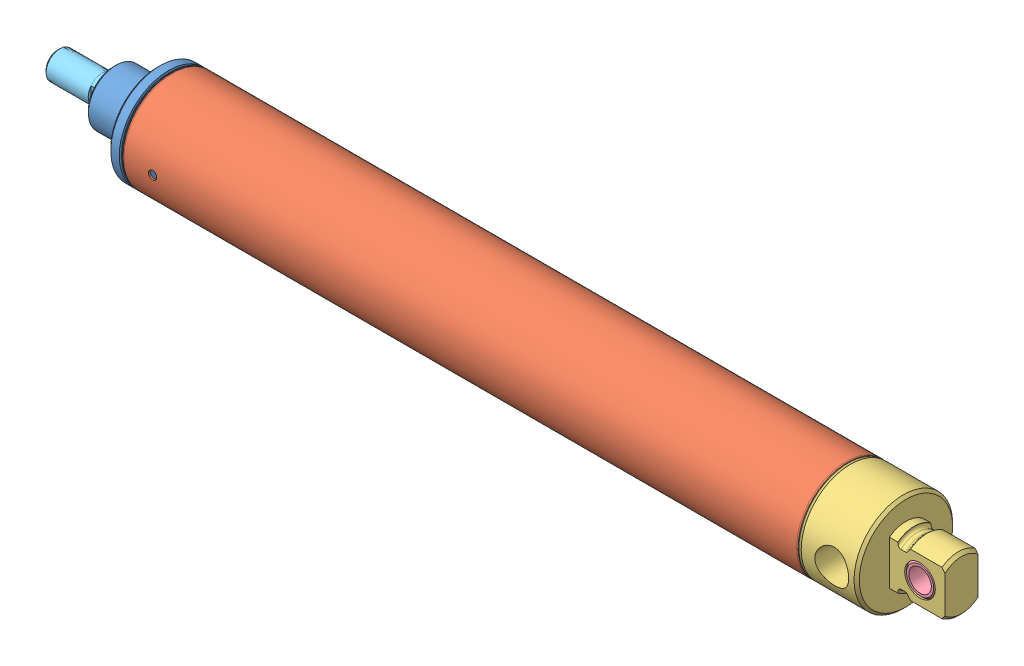
SolidWorks assembly 093_5-HPY, configuration Default. Lengths in mm.
Overall size (258.6 28.27 28.27).
6 component instances, 6 part files, 14 mates.
Components (placement in the parent):
- 093_5-HPCY0000_0_dummy-1: 093_5-HPCY0000_0_dummy [Default] at origin
- 09000-0_rod_guide-1: 09000-0_rod_guide [Default] at origin size (25.4 28.27 28.27)
- 09-7_6212C-1: 09-7_6212C [Default] at (16.637 0 0) size (194.93 28.27 28.27)
- 09P0Y000_rear_head-1: 09P0Y000_rear_head [Default] at (204.6224 0 0) size (38.1 28.22 28.22)
- D-3543-1: D-3543 [Default] at (235.585 0 0) x (1 0 0) z (0 0 -1) size (8.78 8.78 9.4)
- C-093_5-HPY0_rod-1: C-093_5-HPY0_rod [Default] at origin size (220.5 27.11 27.11)
Mates (geometry in assembly coordinates):
- Distance2: distance = 0 mm aligned: plane of 09000-0_rod_guide-1 through (0 0 0) normal (1 0 0); plane of 093_5-HPCY0000_0_dummy-1 through (0 0 0) normal (1 0 0)
- Coincident1: coincident aligned: line of 093_5-HPCY0000_0_dummy-1 through (80.9 0 0) axis (-1 0 0); line of 09000-0_rod_guide-1 through (80.9 0 0) axis (-1 0 0)
- Angle3: planar angle = 0 rad aligned: plane of 09000-0_rod_guide-1 through (0 0 0) normal (0 0 -1); plane of 093_5-HPCY0000_0_dummy-1 through (0 0 0) normal (0 0 -1)
- Distance4: distance = 0 mm aligned: plane of 09-7_6212C-1 through (16.637 0 0) normal (1 0 0); plane of 09000-0_rod_guide-1 through (16.637 0 0) normal (1 0 0)
- Coincident2: coincident aligned: line of 09000-0_rod_guide-1 through (80.9 0 0) axis (-1 0 0); line of 09-7_6212C-1 through (97.537 0 0) axis (-1 0 0)
- Angle6: planar angle = 0 rad aligned: plane of 09-7_6212C-1 through (16.637 0 0) normal (0 0 -1); plane of 09000-0_rod_guide-1 through (0 0 0) normal (0 0 -1)
- Distance6: distance = 0 mm aligned: plane of 09P0Y000_rear_head-1 through (210.2104 0 0) normal (1 0 0); plane of 09-7_6212C-1 through (210.2104 0 0) normal (1 0 0)
- Coincident3: coincident aligned: line of 09-7_6212C-1 through (97.537 0 0) axis (-1 0 0); line of 09P0Y000_rear_head-1 through (285.5224 0 0) axis (-1 0 0)
- Angle9: planar angle = 0 rad aligned: plane of 09P0Y000_rear_head-1 through (204.6224 0 0) normal (0 0 -1); plane of 09-7_6212C-1 through (16.637 0 0) normal (0 0 -1)
- Distance7: distance = 0 mm anti-aligned: plane of D-3543-1 through (235.585 0 0) normal (0 0 -1); plane of 09P0Y000_rear_head-1 through (204.6224 0 0) normal (0 0 1)
- Coincident4: coincident anti-aligned: line of 09P0Y000_rear_head-1 through (235.585 0 80.9) axis (0 0 -1); line of D-3543-1 through (235.585 0 -80.9) axis (0 0 1)
- Angle12: planar angle = 0 rad aligned: plane of D-3543-1; plane of 09P0Y000_rear_head-1 through (235.585 0 0) normal (1 0 0)
- LimitDistance2: limit distance = 0 mm aligned: plane of C-093_5-HPY0_rod-1 through (0 0 0) normal (1 0 0); plane of 09000-0_rod_guide-1 through (0 0 0) normal (1 0 0)
- Coincident5: coincident aligned: line of 09000-0_rod_guide-1 through (80.9 0 0) axis (-1 0 0); line of C-093_5-HPY0_rod-1 through (80.9 0 0) axis (-1 0 0)
